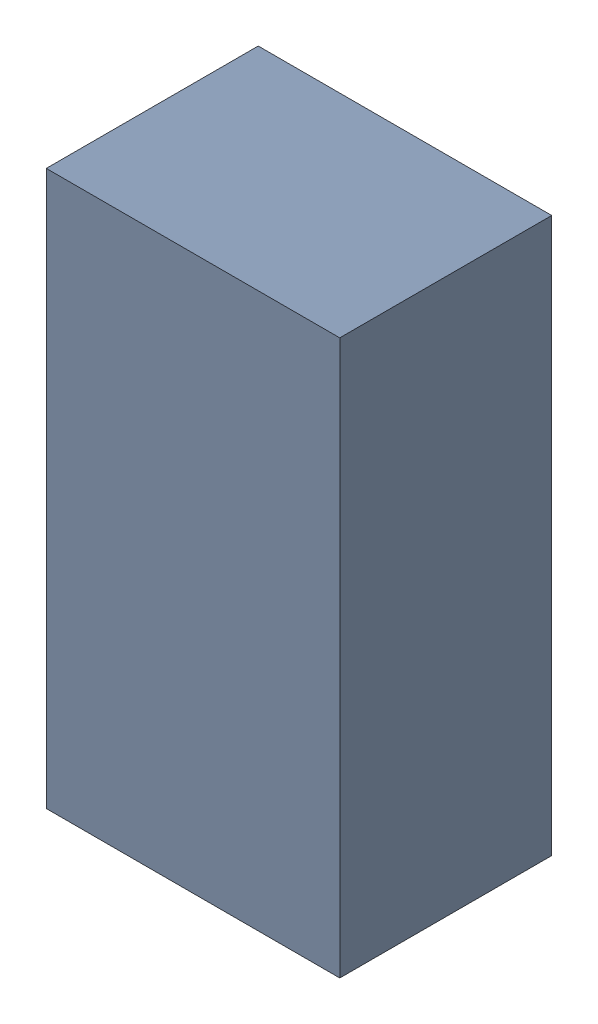
SolidWorks assembly C2, configuration Default. Lengths in mm.
Overall size (1.8 3.4 1.3).
2 component instances, 1 part files, 0 mates.
Components (placement in the parent):
- 5920131968-1: 5920131968 [Default] at (35 32.25 0) size (1.8 3.4 1.3)
  - Extruded_2-1: Extruded_2 [Default] at origin size (1.8 3.4 1.3)
